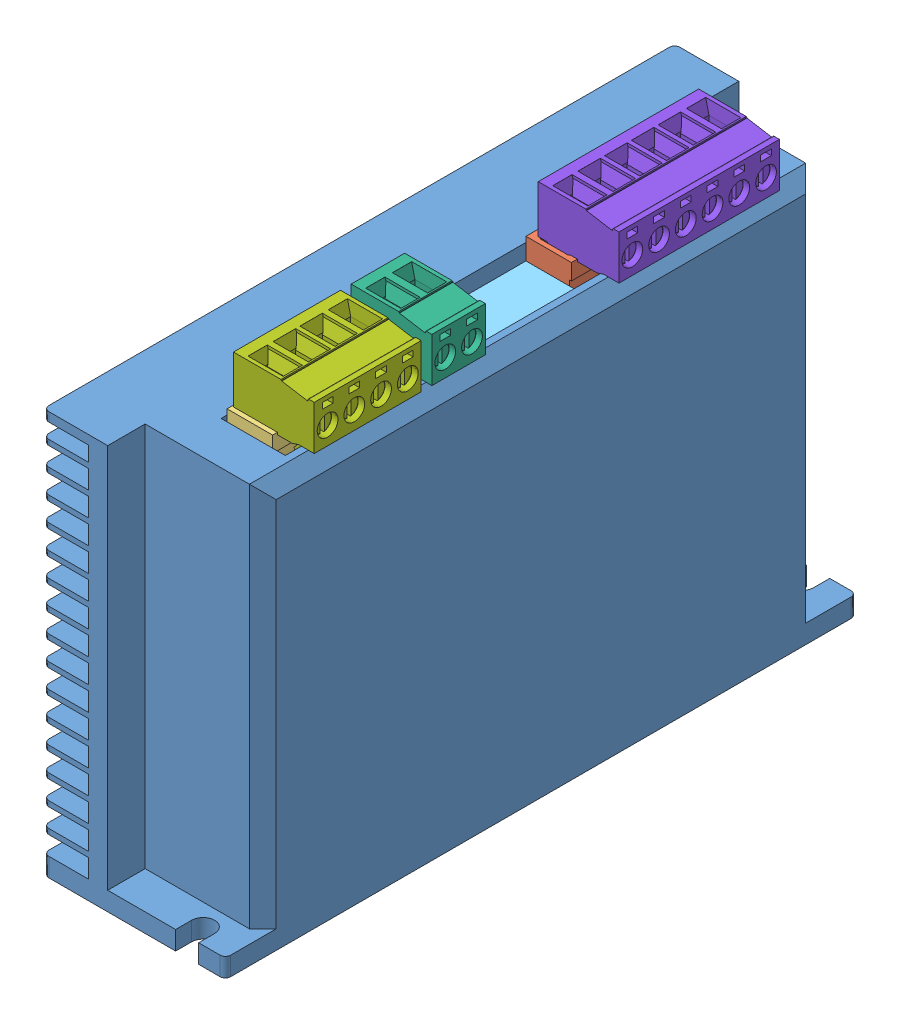
SolidWorks assembly m542, configuration Default. Lengths in mm.
Overall size (35.49 86.4 118).
8 component instances, 8 part files, 0 mates.
Components (placement in the parent):
- M542-1: M542 [Default] at origin size (34 75.5 118)
- klemmleisten_a-tb500-oq06cv-1: klemmleisten_a-tb500-oq06cv [Default] at (19.2 77.5 31) x (0 0 1) z (0 1 0) size (32 8.5 16.01)
- klemmleisten_a-tb500-oq04cv-1: klemmleisten_a-tb500-oq04cv [Default] at (19.2 77.5 91.88) x (0 0 1) z (0 1 0) size (22 8.5 16.01)
- klemmleisten_a-tb500-oq02cv-1: klemmleisten_a-tb500-oq02cv [Default] at (19.2 77.5 74.88) x (0 0 1) z (0 1 0) size (12 8.5 16.01)
- 19648-1: 19648 [Default] at (16 68.1 57.94) x (0 0 1) z (0 1 0) size (21.88 13.4 10.8)
- klemmleisten_a-tb500-tj02-1: klemmleisten_a-tb500-tj02 [Default] at (19.5012 77.5 74.98) x (0 0 1) z (0 1 0) size (10 15.09 18.2)
- klemmleisten_a-tb500-tj04-1: klemmleisten_a-tb500-tj04 [Default] at (19.5012 77.5 91.98) x (0 0 1) z (0 1 0) size (20 15.09 18.2)
- klemmleisten_a-tb500-tj06-1: klemmleisten_a-tb500-tj06 [Default] at (20.4 77.5 30.9) x (0 0 1) z (0 1 0) size (30 15.09 18.2)
